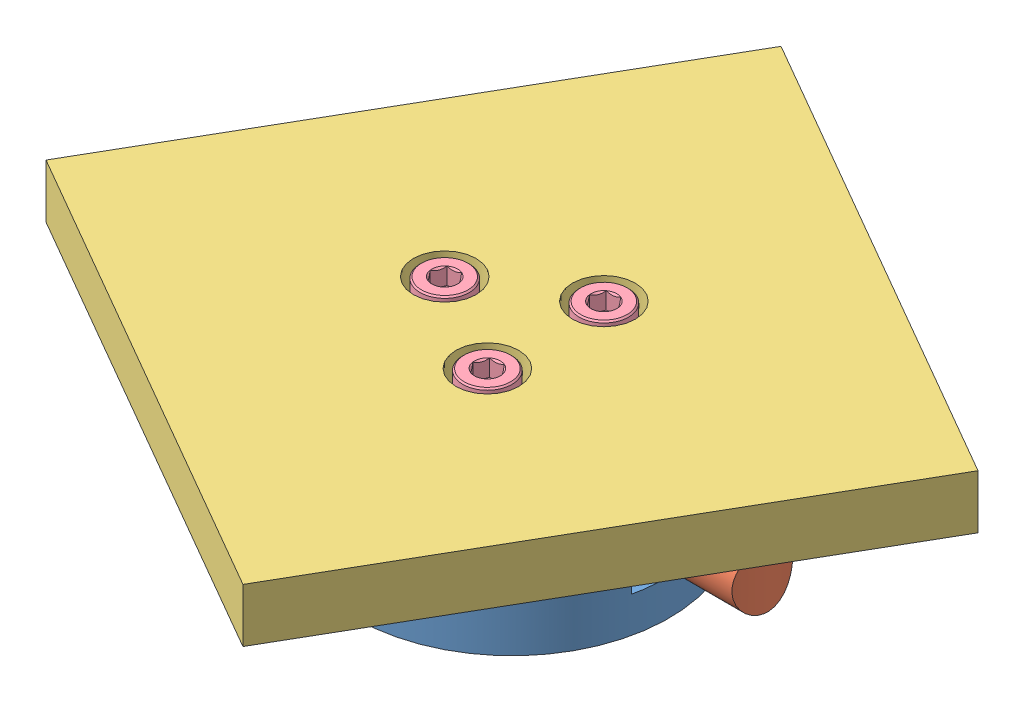
SolidWorks assembly load_cell_calibration_assy, configuration Default. Lengths in mm.
Overall size (86.71 20.64 81.96).
6 component instances, 4 part files, 12 mates.
Components (placement in the parent):
- mount-1: mount [Default] at origin size (63.23 11 35)
- TAS606-1: TAS606 [Default] at (0 0.5 0) x (0 0 1) z (1 0 0) size (20 12 38.52)
- plate-1: plate [Default] at (0 10.5 0) x (0.866025 0 0.5) z (-0.5 0 0.866025) size (60 6 60)
- 91290A111_BLACK-OXIDE CLASS 12.9 SOCKET HEAD CAP SCREW-1: 91290A111_BLACK-OXIDE CLASS 12.9 SOCKET HEAD CAP SCREW [91290A111] at (-7.5 7.5 0) x (0.790201 0 -0.612848) z (0 -1 0) size (5.5 5.5 9.19)
- 91290A111_BLACK-OXIDE CLASS 12.9 SOCKET HEAD CAP SCREW-2: 91290A111_BLACK-OXIDE CLASS 12.9 SOCKET HEAD CAP SCREW [91290A111] at (3.75 7.5 -6.4952) x (0.790201 0 -0.612848) z (0 -1 0) size (5.5 5.5 9.19)
- 91290A111_BLACK-OXIDE CLASS 12.9 SOCKET HEAD CAP SCREW-3: 91290A111_BLACK-OXIDE CLASS 12.9 SOCKET HEAD CAP SCREW [91290A111] at (3.75 7.5 6.4952) x (0.790201 0 -0.612848) z (0 -1 0) size (5.5 5.5 9.19)
Mates (geometry in assembly coordinates):
- Concentric1: concentric aligned: cylinder of mount-1 through (0 -1.5 0) axis (0 1 0) radius 1.2; cylinder of TAS606-1 through (0 -1.5 0) axis (0 1 0) radius 1.15
- Coincident1: coincident anti-aligned: plane of mount-1 through (0 -1.5 0) normal (0 1 0); plane of TAS606-1 through (0 -1.5 0) normal (0 -1 0)
- Parallel1: parallel aligned: line of mount-1 through (45.7319 0 0) axis (0 1 0); face of TAS606-1
- Concentric2: concentric aligned: cylinder of TAS606-1 through (3.75 5.5 -6.4952) axis (0 1 0) radius 1.5; cylinder of plate-1 through (3.75 13.5 -6.4952) axis (0 1 0) radius 3.5
- Coincident2: coincident anti-aligned: plane of TAS606-1 through (0 10.5 0) normal (0 1 0); plane of plate-1 through (0 10.5 0) normal (0 -1 0)
- Concentric3: concentric anti-aligned: cylinder of TAS606-1 through (3.75 5.5 6.4952) axis (0 1 0) radius 1.5; cylinder of plate-1 through (3.75 16.5 6.4952) axis (0 -1 0) radius 2
- Concentric4: concentric anti-aligned: cylinder of plate-1 through (-7.5 13.5 0) axis (0 1 0) radius 3.5; cylinder of 91290A111_BLACK-OXIDE CLASS 12.9 SOCKET HEAD CAP SCREW-1 through (-7.5 16.5 0) axis (0 -1 0) radius 2.75
- Coincident3: coincident anti-aligned: plane of plate-1 through (-7.5 13.5 0) normal (0 1 0); plane of 91290A111_BLACK-OXIDE CLASS 12.9 SOCKET HEAD CAP SCREW-1 through (-7.5 13.5 0) normal (0 -1 0)
- Concentric5: concentric anti-aligned: cylinder of plate-1 through (3.75 13.5 6.4952) axis (0 1 0) radius 3.5; cylinder of 91290A111_BLACK-OXIDE CLASS 12.9 SOCKET HEAD CAP SCREW-3 through (3.75 16.5 6.4952) axis (0 -1 0) radius 2.75
- Concentric6: concentric anti-aligned: cylinder of plate-1 through (3.75 13.5 -6.4952) axis (0 1 0) radius 3.5; cylinder of 91290A111_BLACK-OXIDE CLASS 12.9 SOCKET HEAD CAP SCREW-2 through (3.75 16.5 -6.4952) axis (0 -1 0) radius 2.75
- Coincident4: coincident anti-aligned: plane of plate-1 through (3.75 13.5 6.4952) normal (0 1 0); plane of 91290A111_BLACK-OXIDE CLASS 12.9 SOCKET HEAD CAP SCREW-3 through (3.75 13.5 6.4952) normal (0 -1 0)
- Coincident5: coincident anti-aligned: plane of plate-1 through (3.75 13.5 -6.4952) normal (0 1 0); plane of 91290A111_BLACK-OXIDE CLASS 12.9 SOCKET HEAD CAP SCREW-2 through (3.75 13.5 -6.4952) normal (0 -1 0)
